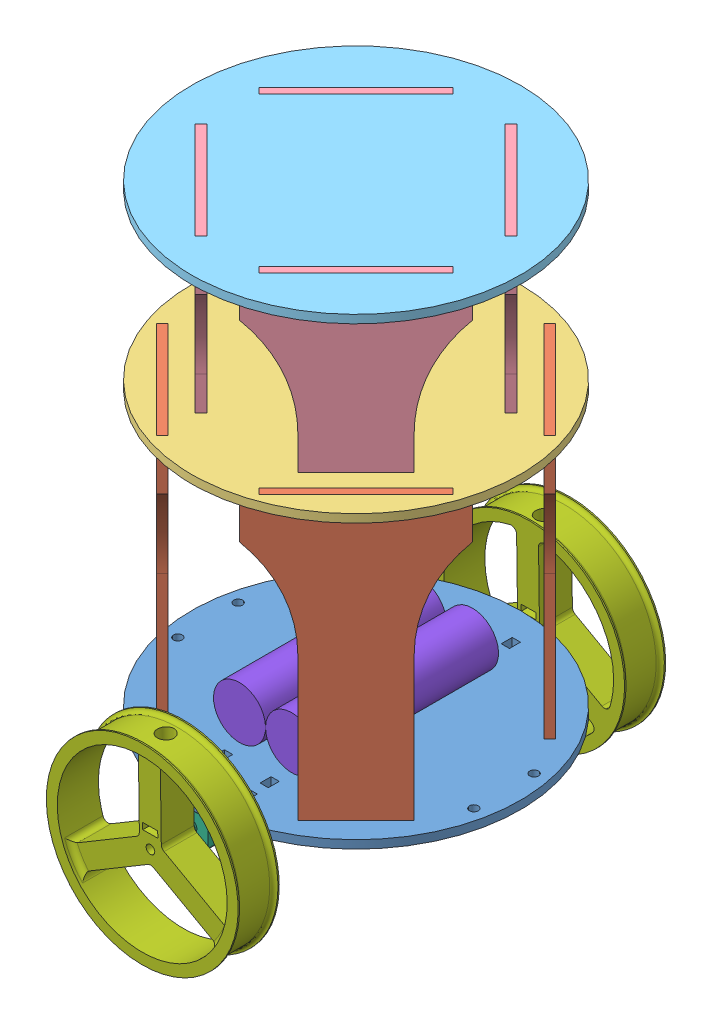
SolidWorks assembly Pisa, configuration Valor predeterminado. Lengths in mm.
Overall size (120 209.48 156).
18 component instances, 8 part files, 21 mates.
Components (placement in the parent):
- Base-1: Base [Valor predeterminado] at origin size (120 3 120)
- haste-1: haste [Valor predeterminado] at (-35.3553 45.5 35.3553) x (0.707107 0 0.707107) z (-0.707107 0 0.707107) size (60 106 3)
- haste-2: haste [Valor predeterminado] at (-35.3553 45.5 -35.3553) x (-0.707107 0 0.707107) z (-0.707107 0 -0.707107) size (60 106 3)
- haste-3: haste [Valor predeterminado] at (35.3553 45.5 -35.3553) x (-0.707107 0 -0.707107) z (0.707107 0 -0.707107) size (60 106 3)
- haste-4: haste [Valor predeterminado] at (35.3553 45.5 35.3553) x (0.707107 0 -0.707107) z (0.707107 0 0.707107) size (60 106 3)
- Base 2-1: Base 2 [Valor predeterminado] at (0 103 0) size (120 3 120)
- haste superior-1: haste superior [Valor predeterminado] at (-28.2843 128.5 28.2843) x (0.707107 0 0.707107) z (-0.707107 0 0.707107) size (60 66 3)
- haste superior-2: haste superior [Valor predeterminado] at (-28.2843 128.5 -28.2843) x (-0.707107 0 0.707107) z (-0.707107 0 -0.707107) size (60 66 3)
- haste superior-3: haste superior [Valor predeterminado] at (28.2843 128.5 -28.2843) x (-0.707107 0 -0.707107) z (0.707107 0 -0.707107) size (60 66 3)
- haste superior-4: haste superior [Valor predeterminado] at (28.2843 128.5 28.2843) x (0.707107 0 -0.707107) z (0.707107 0 0.707107) size (60 66 3)
- Base 3-1: Base 3 [Valor predeterminado] at (0 166 0) size (120 3 120)
- 298,1 Micro Metal Gearmotor MP-1: 298,1 Micro Metal Gearmotor MP [Predeterminado] at (6 -11.49 51) x (0 1 0) z (0 0 1) size (10.11 12.21 36.61)
- 298,1 Micro Metal Gearmotor MP-2: 298,1 Micro Metal Gearmotor MP [Predeterminado] at (6 -1.49 -51) x (0 -1 0) z (0 0 -1) size (10.11 12.21 36.61)
- Roda 40mm c Porca2-1: Roda 40mm c Porca2 [Valor predeterminado] at (0 -6.49 63) x (0.999902 0.01402 0) z (0 0 1) size (70 70 15)
- Roda 40mm c Porca2-2: Roda 40mm c Porca2 [Valor predeterminado] at (0 -6.49 -63) x (-0.999902 -0.01402 0) z (0 0 -1) size (70 70 15)
- Bateria-1: Bateria [Valor predeterminado] at (12.3338 11.9257 -66) x (0.999436 -0.033594 0) z (0 0 1) size (41.7 26.42 66)
  - Célula Bateria-1: Célula Bateria [Valor predeterminado] at (-2.8011 -1.0204 33) size (19 19 66)
  - Célula Bateria-2: Célula Bateria [Valor predeterminado] at (-21.7903 -1.6587 33) x (0.824573 -0.565755 0) z (0 0 1) size (19 19 66)
Mates (geometry in assembly coordinates):
- Coincident1: coincident aligned: plane of Base-1 through (0 -1.5 0) normal (0 -1 0); plane of haste-1 through (-43.4871 -1.5 29.3449) normal (0 -1 0)
- Coincident2: coincident anti-aligned: plane of Base-1 through (-41.3657 -1.5 27.2236) normal (0.707107 0 0.707107); plane of haste-1 through (-43.4871 1.5 29.3449) normal (-0.707107 0 -0.707107)
- Coincident3: coincident anti-aligned: plane of Base-1 through (-29.3449 -1.5 43.4871) normal (0.707107 0 -0.707107); plane of haste-1 through (-36.416 45.5 36.416) normal (-0.707107 0 0.707107)
- Concentric1: concentric aligned: cylinder of Base-1 through (0 1.5 0) axis (0 -1 0) radius 60; cylinder of Base 2-1 through (0 104.5 0) axis (0 -1 0) radius 60
- Coincident4: coincident aligned: plane of haste-1 through (-54.0937 104.5 18.7383) normal (0 1 0); plane of Base 2-1 through (0 104.5 0) normal (0 1 0)
- Parallel1: parallel aligned: plane of haste-1 through (-34.2947 45.5 34.2947) normal (0.707107 0 -0.707107); plane of Base 2-1 through (-18.7383 101.5 54.0937) normal (0.707107 0 -0.707107)
- Coincident6: coincident anti-aligned: plane of Base 2-1 through (-22.2739 101.5 36.416) normal (0.707107 0 -0.707107); plane of haste superior-1 through (-29.3449 128.5 29.3449) normal (-0.707107 0 0.707107)
- Coincident7: coincident aligned: plane of Base 2-1 through (0 101.5 0) normal (0 -1 0); plane of haste superior-1 through (-36.416 101.5 22.2739) normal (0 -1 0)
- Coincident8: coincident anti-aligned: plane of Base 2-1 through (-36.416 101.5 22.2739) normal (0.707107 0 0.707107); plane of haste superior-1 through (-36.416 104.5 22.2739) normal (-0.707107 0 -0.707107)
- Coincident9: coincident aligned: plane of haste superior-2 through (-11.6673 167.5 -47.0226) normal (0 1 0); plane of Base 3-1 through (0 167.5 0) normal (0 1 0)
- Coincident10: coincident anti-aligned: plane of haste superior-2 through (-29.3449 128.5 -29.3449) normal (-0.707107 0 -0.707107); plane of Base 3-1 through (-47.0226 164.5 -11.6673) normal (0.707107 0 0.707107)
- Coincident11: coincident anti-aligned: plane of haste superior-2 through (-11.6673 167.5 -47.0226) normal (0.707107 0 -0.707107); plane of Base 3-1 through (-9.5459 164.5 -44.9013) normal (-0.707107 0 0.707107)
- Width1: width anti-aligned: plane of Base-1 through (-10 -1.5 50) normal (1 0 0); plane of Base-1 through (10 -1.5 50) normal (-1 0 0); plane of 298,1 Micro Metal Gearmotor MP-1 through (-6 -11.49 60) normal (-1 0 0); plane of 298,1 Micro Metal Gearmotor MP-1 through (6 -11.49 60) normal (1 0 0)
- Coincident12: coincident anti-aligned: plane of Base-1 through (0 -1.5 0) normal (0 -1 0); plane of 298,1 Micro Metal Gearmotor MP-1 through (6 -1.5 51) normal (0 1 0)
- Tangent1: tangent aligned: cylinder of Base-1 through (0 1.5 0) axis (0 -1 0) radius 60; plane of 298,1 Micro Metal Gearmotor MP-1 through (6 -11.49 60) normal (0 0 1)
- Concentric2: concentric anti-aligned: cylinder of 298,1 Micro Metal Gearmotor MP-1 through (0 -6.49 70.6) axis (0 0 -1) radius 1.5; cylinder of Roda 40mm c Porca2-1 through (0 -6.49 63) axis (0 0 1) radius 1.575
- Distance1: distance = 3 mm anti-aligned: plane of Roda 40mm c Porca2-1 through (0 -6.49 63) normal (0 0 -1); plane of 298,1 Micro Metal Gearmotor MP-1 through (6 -11.49 60) normal (0 0 1)
- Tangent2: tangent anti-aligned: plane of Base-1 through (0 1.5 0) normal (0 1 0); cylinder of Bateria-1/Célula Bateria-1 through (9.5 11 33) axis (0 0 -1) radius 9.5
- Tangent3: tangent anti-aligned: plane of Base-1 through (0 1.5 0) normal (0 1 0); cylinder of Bateria-1/Célula Bateria-2 through (-9.5 11 33) axis (0 0 -1) radius 9.5
- Width2: width anti-aligned: plane of Roda 40mm c Porca2-2 through (0 -6.49 -63) normal (0 0 1); plane of Roda 40mm c Porca2-1 through (0 -6.49 63) normal (0 0 -1); plane of Bateria-1/Célula Bateria-1 through (9.5 11 -33) normal (0 0 -1); plane of Bateria-1/Célula Bateria-1 through (9.5 11 33) normal (0 0 1)
- Tangent4: tangent aligned: cylinder of Bateria-1/Célula Bateria-2 through (-9.5 11 33) axis (0 0 -1) radius 9.5; plane of assembly through (0 0 0) normal (1 0 0)
